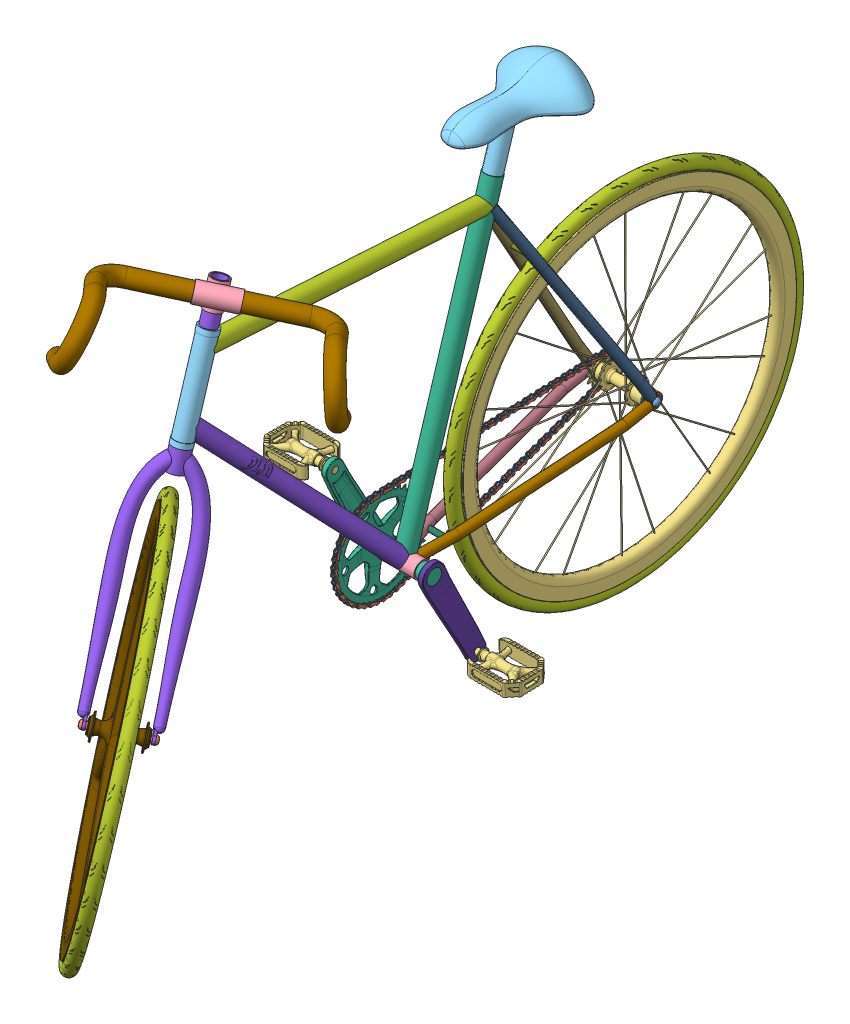
SolidWorks assembly Fixie 2 Virtual, configuration Default. Lengths in mm.
Overall size (654.43 1184.66 1918.44).
126 component instances, 27 part files, 36 mates.
Components (placement in the parent):
- Copy of Axe 2^Fixie 2 Virtual-1: Copy of Axe 2^Fixie 2 Virtual [Default] at (0 85.0139 -432.7378) x (1 0 0) z (0 0.996852 0.079286) size (142 15 15) (virtual)
- Copy of Axe^Fixie 2 Virtual-1: Copy of Axe^Fixie 2 Virtual [Default] at (68.9988 54.6364 630.7845) x (-0.06655 -0.973594 0.21837) z (0.751571 -0.192864 -0.630828) size (15 15 115) (virtual)
- Copy of Back Wheel^Fixie 2 Virtual-1: Copy of Back Wheel^Fixie 2 Virtual [Default] at (0.5 85.0139 -432.7378) x (1 0 0) z (0 0.746338 0.665567) size (100 658.88 658.88) (virtual)
- Copy of cadre^Fixie 2 Virtual-1: Copy of cadre^Fixie 2 Virtual [Défaut] at origin size (140 613.27 908.21) (virtual)
  - tube pedalier^Copy of cadre_Fixie 2 Virtual-1: tube pedalier^Copy of cadre_Fixie 2 Virtual [Défaut] at origin size (73 33 33) (virtual)
  - trou pour fourche^Copy of cadre_Fixie 2 Virtual-2: trou pour fourche^Copy of cadre_Fixie 2 Virtual [Défaut] at (0 502.9172 411.5258) x (0.998411 0.016475 0.053886) z (0 -0.956305 0.292372) size (35 35 185) (virtual)
  - tube de selle^Copy of cadre_Fixie 2 Virtual-1: tube de selle^Copy of cadre_Fixie 2 Virtual [Défaut] at (0 573.7829 -175.423) x (1 0 0) z (0 0.956305 -0.292372) size (32.9 32.9 600.3) (virtual)
  - tube de tete^Copy of cadre_Fixie 2 Virtual-1: tube de tete^Copy of cadre_Fixie 2 Virtual [Défaut] at (0 561.2509 393.6914) x (1 0 0) z (0 0.060491 0.998169) size (32.9 32.9 555.16) (virtual)
  - tube du bas^Copy of cadre_Fixie 2 Virtual-3: tube du bas^Copy of cadre_Fixie 2 Virtual [Défaut] at (0 447.1547 428.5741) x (-1 0 0) z (0 -0.721947 -0.691948) size (32.91 32.9 618.4) (virtual)
  - tube arriere bas^Copy of cadre_Fixie 2 Virtual-2: tube arriere bas^Copy of cadre_Fixie 2 Virtual [Défaut] at origin size (67.83 98.35 411.57) (virtual)
  - tube arriere haut^Copy of cadre_Fixie 2 Virtual-1: tube arriere haut^Copy of cadre_Fixie 2 Virtual [Défaut] at origin size (69.56 441.01 279.99) (virtual)
  - encoche roue^Copy of cadre_Fixie 2 Virtual-7: encoche roue^Copy of cadre_Fixie 2 Virtual [Défaut] at (61 85.0139 -432.7378) x (0 -0.852467 -0.522781) z (-1 0 0) size (54 61.43 6.25) (virtual)
  - Symétrietube arriere haut^Copy of cadre_Fixie 2 Virtual-2: Symétrietube arriere haut^Copy of cadre_Fixie 2 Virtual [Défaut] x (-1 0 0) z (0 0 -1) size (69.56 441.01 279.99) (virtual)
  - Symétrietube arriere bas^Copy of cadre_Fixie 2 Virtual-3: Symétrietube arriere bas^Copy of cadre_Fixie 2 Virtual [Défaut] x (-1 0 0) z (0 0 -1) size (67.83 98.35 411.57) (virtual)
  - Symétrieencoche roue^Copy of cadre_Fixie 2 Virtual-8: Symétrieencoche roue^Copy of cadre_Fixie 2 Virtual [Défaut] at (-61 85.0139 -432.7378) x (0 -0.852467 -0.522781) z (-1 0 0) size (54 61.43 6.25) (virtual)
  - tube consolider 1^Copy of cadre_Fixie 2 Virtual-1: tube consolider 1^Copy of cadre_Fixie 2 Virtual [Défaut] x (0 0 -1) z (1 0 0) size (10 10 30.38) (virtual)
  - tube consolider 2^Copy of cadre_Fixie 2 Virtual-1: tube consolider 2^Copy of cadre_Fixie 2 Virtual [Défaut] x (0 0 -1) z (1 0 0) size (10 10 34.39) (virtual)
- Copy of Crank 2^Fixie 2 Virtual-1: Copy of Crank 2^Fixie 2 Virtual [Default] at (65 -161.4318 -97.9912) x (0 -0.413351 0.910572) z (-1 0 0) size (45 210 26.78) (virtual)
- Copy of Front Wheel^Fixie 2 Virtual-1: Copy of Front Wheel^Fixie 2 Virtual [Default] at (68.9988 54.6364 630.7845) x (-0.751571 0.192864 0.630828) z (0.306423 0.94894 0.074953) size (90 658.88 658.88) (virtual)
- Copy of Inner Chain^Fixie 2 Virtual-1: Copy of Inner Chain^Fixie 2 Virtual [Default] at (-46 13.7146 89.7835) x (1 0 0) z (0 0.988534 -0.151) size (5 8 20.8) (virtual)
- Copy of Outter Chain^Fixie 2 Virtual-1: Copy of Outter Chain^Fixie 2 Virtual [Default] at (-46 26.1669 86.9739) x (1 0 0) z (0 0.957599 -0.288103) size (8.5 8 20.8) (virtual)
- Copy of Pedal 2^Fixie 2 Virtual-1: Copy of Pedal 2^Fixie 2 Virtual [Default] at (-136.5 154.7972 70.2697) x (0 0 1) z (1 0 0) size (80 25 117.5) (virtual)
- Copy of Potence 2^Fixie 2 Virtual-1: Copy of Potence 2^Fixie 2 Virtual [Défaut] at (42.681 674.7582 409.8391) x (-0.659652 -0.219738 -0.718731) z (0.751571 -0.192864 -0.630828) size (98.9 64.61 70) (virtual)
- Copy of selle^Fixie 2 Virtual-1: Copy of selle^Fixie 2 Virtual [Défaut] at (0 662.8695 -204.4368) x (-1 0 0) z (0 0.017452 -0.999848) size (178.5 284.14 238.49) (virtual)
- Copy of Sprocket 2^Fixie 2 Virtual-1: Copy of Sprocket 2^Fixie 2 Virtual [Default] at (-50 0 0) x (-1 0 0) z (0 0.869629 -0.493706) size (135 250.05 212.39) (virtual)
- Copy of Tire^Fixie 2 Virtual-1: Copy of Tire^Fixie 2 Virtual [Default] at (0.5 85.0139 -432.7378) x (1 0 0) z (0 -0.189149 0.981948) size (24.5 700 700) (virtual)
- Copy of Pedal 2^Fixie 2 Virtual-2: Copy of Pedal 2^Fixie 2 Virtual [Default] at (136.5 -154.7972 -70.2697) x (0 0.031063 -0.999517) z (-1 0 0) size (80 25 117.5) (virtual)
- Copy of Tire^Fixie 2 Virtual-2: Copy of Tire^Fixie 2 Virtual [Default] at (68.9988 54.6364 630.7845) x (-0.751571 0.192864 0.630828) z (-0.630828 -0.489733 -0.601845) size (24.5 700 700) (virtual)
- Copy of Inner Chain^Fixie 2 Virtual-50: Copy of Inner Chain^Fixie 2 Virtual [Default] at (-46 38.1023 82.4462) x (1 0 0) z (0 0.907749 -0.419514) size (5 8 20.8) (virtual)
- Copy of Inner Chain^Fixie 2 Virtual-51: Copy of Inner Chain^Fixie 2 Virtual [Default] at (-46 59.4943 68.6265) x (1 0 0) z (0 0.755591 -0.655044) size (5 8 20.8) (virtual)
- Copy of Inner Chain^Fixie 2 Virtual-52: Copy of Inner Chain^Fixie 2 Virtual [Default] at (-46 76.2084 49.4109) x (1 0 0) z (0 0.544024 -0.83907) size (5 8 20.8) (virtual)
- Copy of Inner Chain^Fixie 2 Virtual-53: Copy of Inner Chain^Fixie 2 Virtual [Default] at (-46 86.9306 26.3104) x (1 0 0) z (0 0.289683 -0.957123) size (5 8 20.8) (virtual)
- Copy of Inner Chain^Fixie 2 Virtual-54: Copy of Inner Chain^Fixie 2 Virtual [Default] at (-46 91.0468 1.1482) x (1 0 0) z (0 0.04837 -0.998829) size (5 8 20.8) (virtual)
- Copy of Inner Chain^Fixie 2 Virtual-55: Copy of Inner Chain^Fixie 2 Virtual [Default] at (-46 92.1741 -24.4209) x (1 0 0) z (0 0.042605 -0.999092) size (5 8 20.8) (virtual)
- Copy of Inner Chain^Fixie 2 Virtual-56: Copy of Inner Chain^Fixie 2 Virtual [Default] at (-46 93.2646 -49.9916) x (1 0 0) z (0 0.042605 -0.999092) size (5 8 20.8) (virtual)
- Copy of Inner Chain^Fixie 2 Virtual-57: Copy of Inner Chain^Fixie 2 Virtual [Default] at (-46 94.355 -75.5624) x (1 0 0) z (0 0.042605 -0.999092) size (5 8 20.8) (virtual)
- Copy of Inner Chain^Fixie 2 Virtual-58: Copy of Inner Chain^Fixie 2 Virtual [Default] at (-46 95.4454 -101.1332) x (1 0 0) z (0 0.042605 -0.999092) size (5 8 20.8) (virtual)
- Copy of Inner Chain^Fixie 2 Virtual-59: Copy of Inner Chain^Fixie 2 Virtual [Default] at (-46 96.5358 -126.7039) x (1 0 0) z (0 0.042605 -0.999092) size (5 8 20.8) (virtual)
- Copy of Inner Chain^Fixie 2 Virtual-60: Copy of Inner Chain^Fixie 2 Virtual [Default] at (-46 97.6263 -152.2747) x (1 0 0) z (0 0.042605 -0.999092) size (5 8 20.8) (virtual)
- Copy of Inner Chain^Fixie 2 Virtual-61: Copy of Inner Chain^Fixie 2 Virtual [Default] at (-46 98.7167 -177.8454) x (1 0 0) z (0 0.042605 -0.999092) size (5 8 20.8) (virtual)
- Copy of Inner Chain^Fixie 2 Virtual-62: Copy of Inner Chain^Fixie 2 Virtual [Default] at (-46 99.8071 -203.4162) x (1 0 0) z (0 0.042605 -0.999092) size (5 8 20.8) (virtual)
- Copy of Inner Chain^Fixie 2 Virtual-63: Copy of Inner Chain^Fixie 2 Virtual [Default] at (-46 100.8975 -228.987) x (1 0 0) z (0 0.042605 -0.999092) size (5 8 20.8) (virtual)
- Copy of Inner Chain^Fixie 2 Virtual-64: Copy of Inner Chain^Fixie 2 Virtual [Default] at (-46 101.988 -254.5577) x (1 0 0) z (0 0.042605 -0.999092) size (5 8 20.8) (virtual)
- Copy of Inner Chain^Fixie 2 Virtual-65: Copy of Inner Chain^Fixie 2 Virtual [Default] at (-46 103.0784 -280.1285) x (1 0 0) z (0 0.042605 -0.999092) size (5 8 20.8) (virtual)
- Copy of Inner Chain^Fixie 2 Virtual-66: Copy of Inner Chain^Fixie 2 Virtual [Default] at (-46 104.1688 -305.6992) x (1 0 0) z (0 0.042605 -0.999092) size (5 8 20.8) (virtual)
- Copy of Inner Chain^Fixie 2 Virtual-67: Copy of Inner Chain^Fixie 2 Virtual [Default] at (-46 105.2592 -331.27) x (1 0 0) z (0 0.042605 -0.999092) size (5 8 20.8) (virtual)
- Copy of Inner Chain^Fixie 2 Virtual-68: Copy of Inner Chain^Fixie 2 Virtual [Default] at (-46 106.3497 -356.8408) x (1 0 0) z (0 0.042605 -0.999092) size (5 8 20.8) (virtual)
- Copy of Inner Chain^Fixie 2 Virtual-69: Copy of Inner Chain^Fixie 2 Virtual [Default] at (-46 107.4401 -382.4115) x (1 0 0) z (0 0.042605 -0.999092) size (5 8 20.8) (virtual)
- Copy of Inner Chain^Fixie 2 Virtual-70: Copy of Inner Chain^Fixie 2 Virtual [Default] at (-46 108.5305 -407.9823) x (1 0 0) z (0 0.042605 -0.999092) size (5 8 20.8) (virtual)
- Copy of Inner Chain^Fixie 2 Virtual-71: Copy of Inner Chain^Fixie 2 Virtual [Default] at (-46 108.9178 -433.5444) x (1 0 0) z (0 -0.06729 -0.997733) size (5 8 20.8) (virtual)
- Copy of Inner Chain^Fixie 2 Virtual-72: Copy of Inner Chain^Fixie 2 Virtual [Default] at (-46 96.0116 -453.7333) x (1 0 0) z (0 -0.885831 -0.464009) size (5 8 20.8) (virtual)
- Copy of Inner Chain^Fixie 2 Virtual-73: Copy of Inner Chain^Fixie 2 Virtual [Default] at (-46 72.1801 -452.6641) x (1 0 0) z (0 -0.840718 0.541474) size (5 8 20.8) (virtual)
- Copy of Inner Chain^Fixie 2 Virtual-74: Copy of Inner Chain^Fixie 2 Virtual [Default] at (-46 58.6166 -431.8851) x (1 0 0) z (0 -0.338529 0.940956) size (5 8 20.8) (virtual)
- Copy of Inner Chain^Fixie 2 Virtual-75: Copy of Inner Chain^Fixie 2 Virtual [Default] at (-46 49.9523 -407.8023) x (1 0 0) z (0 -0.338529 0.940956) size (5 8 20.8) (virtual)
- Copy of Inner Chain^Fixie 2 Virtual-76: Copy of Inner Chain^Fixie 2 Virtual [Default] at (-46 41.288 -383.7195) x (1 0 0) z (0 -0.338529 0.940956) size (5 8 20.8) (virtual)
- Copy of Inner Chain^Fixie 2 Virtual-77: Copy of Inner Chain^Fixie 2 Virtual [Default] at (-46 32.6237 -359.6367) x (1 0 0) z (0 -0.338529 0.940956) size (5 8 20.8) (virtual)
- Copy of Inner Chain^Fixie 2 Virtual-78: Copy of Inner Chain^Fixie 2 Virtual [Default] at (-46 23.9594 -335.5538) x (1 0 0) z (0 -0.338529 0.940956) size (5 8 20.8) (virtual)
- Copy of Inner Chain^Fixie 2 Virtual-79: Copy of Inner Chain^Fixie 2 Virtual [Default] at (-46 15.2951 -311.471) x (1 0 0) z (0 -0.338529 0.940956) size (5 8 20.8) (virtual)
- Copy of Inner Chain^Fixie 2 Virtual-80: Copy of Inner Chain^Fixie 2 Virtual [Default] at (-46 6.6307 -287.3882) x (1 0 0) z (0 -0.338529 0.940956) size (5 8 20.8) (virtual)
- Copy of Inner Chain^Fixie 2 Virtual-81: Copy of Inner Chain^Fixie 2 Virtual [Default] at (-46 -2.0336 -263.3053) x (1 0 0) z (0 -0.338529 0.940956) size (5 8 20.8) (virtual)
- Copy of Inner Chain^Fixie 2 Virtual-82: Copy of Inner Chain^Fixie 2 Virtual [Default] at (-46 -10.6979 -239.2225) x (1 0 0) z (0 -0.338529 0.940956) size (5 8 20.8) (virtual)
- Copy of Inner Chain^Fixie 2 Virtual-83: Copy of Inner Chain^Fixie 2 Virtual [Default] at (-46 -19.3622 -215.1397) x (1 0 0) z (0 -0.338529 0.940956) size (5 8 20.8) (virtual)
- Copy of Inner Chain^Fixie 2 Virtual-84: Copy of Inner Chain^Fixie 2 Virtual [Default] at (-46 -28.0265 -191.0569) x (1 0 0) z (0 -0.338529 0.940956) size (5 8 20.8) (virtual)
- Copy of Inner Chain^Fixie 2 Virtual-85: Copy of Inner Chain^Fixie 2 Virtual [Default] at (-46 -36.6908 -166.974) x (1 0 0) z (0 -0.338529 0.940956) size (5 8 20.8) (virtual)
- Copy of Inner Chain^Fixie 2 Virtual-86: Copy of Inner Chain^Fixie 2 Virtual [Default] at (-46 -45.3551 -142.8912) x (1 0 0) z (0 -0.338529 0.940956) size (5 8 20.8) (virtual)
- Copy of Inner Chain^Fixie 2 Virtual-87: Copy of Inner Chain^Fixie 2 Virtual [Default] at (-46 -54.0194 -118.8084) x (1 0 0) z (0 -0.338529 0.940956) size (5 8 20.8) (virtual)
- Copy of Inner Chain^Fixie 2 Virtual-88: Copy of Inner Chain^Fixie 2 Virtual [Default] at (-46 -62.6837 -94.7256) x (1 0 0) z (0 -0.338529 0.940956) size (5 8 20.8) (virtual)
- Copy of Inner Chain^Fixie 2 Virtual-89: Copy of Inner Chain^Fixie 2 Virtual [Default] at (-46 -71.3481 -70.6427) x (1 0 0) z (0 -0.338529 0.940956) size (5 8 20.8) (virtual)
- Copy of Inner Chain^Fixie 2 Virtual-90: Copy of Inner Chain^Fixie 2 Virtual [Default] at (-46 -80.0124 -46.5599) x (1 0 0) z (0 -0.338529 0.940956) size (5 8 20.8) (virtual)
- Copy of Inner Chain^Fixie 2 Virtual-91: Copy of Inner Chain^Fixie 2 Virtual [Default] at (-46 -88.0489 -22.2835) x (1 0 0) z (0 -0.245346 0.969436) size (5 8 20.8) (virtual)
- Copy of Inner Chain^Fixie 2 Virtual-92: Copy of Inner Chain^Fixie 2 Virtual [Default] at (-46 -90.7741 3.0378) x (1 0 0) z (0 0.033447 0.99944) size (5 8 20.8) (virtual)
- Copy of Inner Chain^Fixie 2 Virtual-93: Copy of Inner Chain^Fixie 2 Virtual [Default] at (-46 -86.3621 28.1204) x (1 0 0) z (0 0.309611 0.950863) size (5 8 20.8) (virtual)
- Copy of Inner Chain^Fixie 2 Virtual-94: Copy of Inner Chain^Fixie 2 Virtual [Default] at (-46 -75.1598 50.9919) x (1 0 0) z (0 0.561431 0.827524) size (5 8 20.8) (virtual)
- Copy of Inner Chain^Fixie 2 Virtual-95: Copy of Inner Chain^Fixie 2 Virtual [Default] at (-46 -58.0479 69.8541) x (1 0 0) z (0 0.769108 0.639119) size (5 8 20.8) (virtual)
- Copy of Inner Chain^Fixie 2 Virtual-96: Copy of Inner Chain^Fixie 2 Virtual [Default] at (-46 -36.372 83.224) x (1 0 0) z (0 0.916313 0.400463) size (5 8 20.8) (virtual)
- Copy of Outter Chain^Fixie 2 Virtual-50: Copy of Outter Chain^Fixie 2 Virtual [Default] at (-46 49.2851 76.2898) x (1 0 0) z (0 0.839966 -0.542639) size (8.5 8 20.8) (virtual)
- Copy of Outter Chain^Fixie 2 Virtual-51: Copy of Outter Chain^Fixie 2 Virtual [Default] at (-46 68.5282 59.6075) x (1 0 0) z (0 0.65629 -0.754509) size (8.5 8 20.8) (virtual)
- Copy of Outter Chain^Fixie 2 Virtual-52: Copy of Outter Chain^Fixie 2 Virtual [Default] at (-46 82.3832 38.2384) x (1 0 0) z (0 0.421012 -0.907055) size (8.5 8 20.8) (virtual)
- Copy of Outter Chain^Fixie 2 Virtual-53: Copy of Outter Chain^Fixie 2 Virtual [Default] at (-46 89.7607 13.8627) x (1 0 0) z (0 0.152632 -0.988283) size (8.5 8 20.8) (virtual)
- Copy of Outter Chain^Fixie 2 Virtual-54: Copy of Outter Chain^Fixie 2 Virtual [Default] at (-46 91.6289 -11.6355) x (1 0 0) z (0 0.042605 -0.999092) size (8.5 8 20.8) (virtual)
- Copy of Outter Chain^Fixie 2 Virtual-55: Copy of Outter Chain^Fixie 2 Virtual [Default] at (-46 92.7194 -37.2063) x (1 0 0) z (0 0.042605 -0.999092) size (8.5 8 20.8) (virtual)
- Copy of Outter Chain^Fixie 2 Virtual-56: Copy of Outter Chain^Fixie 2 Virtual [Default] at (-46 93.8098 -62.777) x (1 0 0) z (0 0.042605 -0.999092) size (8.5 8 20.8) (virtual)
- Copy of Outter Chain^Fixie 2 Virtual-57: Copy of Outter Chain^Fixie 2 Virtual [Default] at (-46 94.9002 -88.3478) x (1 0 0) z (0 0.042605 -0.999092) size (8.5 8 20.8) (virtual)
- Copy of Outter Chain^Fixie 2 Virtual-58: Copy of Outter Chain^Fixie 2 Virtual [Default] at (-46 95.9906 -113.9185) x (1 0 0) z (0 0.042605 -0.999092) size (8.5 8 20.8) (virtual)
- Copy of Outter Chain^Fixie 2 Virtual-59: Copy of Outter Chain^Fixie 2 Virtual [Default] at (-46 97.0811 -139.4893) x (1 0 0) z (0 0.042605 -0.999092) size (8.5 8 20.8) (virtual)
- Copy of Outter Chain^Fixie 2 Virtual-60: Copy of Outter Chain^Fixie 2 Virtual [Default] at (-46 98.1715 -165.0601) x (1 0 0) z (0 0.042605 -0.999092) size (8.5 8 20.8) (virtual)
- Copy of Outter Chain^Fixie 2 Virtual-61: Copy of Outter Chain^Fixie 2 Virtual [Default] at (-46 99.2619 -190.6308) x (1 0 0) z (0 0.042605 -0.999092) size (8.5 8 20.8) (virtual)
- Copy of Outter Chain^Fixie 2 Virtual-62: Copy of Outter Chain^Fixie 2 Virtual [Default] at (-46 100.3523 -216.2016) x (1 0 0) z (0 0.042605 -0.999092) size (8.5 8 20.8) (virtual)
- Copy of Outter Chain^Fixie 2 Virtual-63: Copy of Outter Chain^Fixie 2 Virtual [Default] at (-46 101.4428 -241.7723) x (1 0 0) z (0 0.042605 -0.999092) size (8.5 8 20.8) (virtual)
- Copy of Outter Chain^Fixie 2 Virtual-64: Copy of Outter Chain^Fixie 2 Virtual [Default] at (-46 102.5332 -267.3431) x (1 0 0) z (0 0.042605 -0.999092) size (8.5 8 20.8) (virtual)
- Copy of Outter Chain^Fixie 2 Virtual-65: Copy of Outter Chain^Fixie 2 Virtual [Default] at (-46 103.6236 -292.9139) x (1 0 0) z (0 0.042605 -0.999092) size (8.5 8 20.8) (virtual)
- Copy of Outter Chain^Fixie 2 Virtual-66: Copy of Outter Chain^Fixie 2 Virtual [Default] at (-46 104.714 -318.4846) x (1 0 0) z (0 0.042605 -0.999092) size (8.5 8 20.8) (virtual)
- Copy of Outter Chain^Fixie 2 Virtual-67: Copy of Outter Chain^Fixie 2 Virtual [Default] at (-46 105.8045 -344.0554) x (1 0 0) z (0 0.042605 -0.999092) size (8.5 8 20.8) (virtual)
- Copy of Outter Chain^Fixie 2 Virtual-68: Copy of Outter Chain^Fixie 2 Virtual [Default] at (-46 106.8949 -369.6261) x (1 0 0) z (0 0.042605 -0.999092) size (8.5 8 20.8) (virtual)
- Copy of Outter Chain^Fixie 2 Virtual-69: Copy of Outter Chain^Fixie 2 Virtual [Default] at (-46 107.9853 -395.1969) x (1 0 0) z (0 0.042605 -0.999092) size (8.5 8 20.8) (virtual)
- Copy of Outter Chain^Fixie 2 Virtual-70: Copy of Outter Chain^Fixie 2 Virtual [Default] at (-46 109.0757 -420.7677) x (1 0 0) z (0 0.042605 -0.999092) size (8.5 8 20.8) (virtual)
- Copy of Outter Chain^Fixie 2 Virtual-71: Copy of Outter Chain^Fixie 2 Virtual [Default] at (-46 105.0834 -445.3464) x (1 0 0) z (0 -0.531973 -0.846761) size (8.5 8 20.8) (virtual)
- Copy of Outter Chain^Fixie 2 Virtual-72: Copy of Outter Chain^Fixie 2 Virtual [Default] at (-46 83.9515 -456.4155) x (1 0 0) z (0 -0.998995 0.044822) size (8.5 8 20.8) (virtual)
- Copy of Outter Chain^Fixie 2 Virtual-73: Copy of Outter Chain^Fixie 2 Virtual [Default] at (-46 63.7917 -443.5526) x (1 0 0) z (0 -0.470274 0.882521) size (8.5 8 20.8) (virtual)
- Copy of Outter Chain^Fixie 2 Virtual-74: Copy of Outter Chain^Fixie 2 Virtual [Default] at (-46 54.2845 -419.8437) x (1 0 0) z (0 -0.338529 0.940956) size (8.5 8 20.8) (virtual)
- Copy of Outter Chain^Fixie 2 Virtual-75: Copy of Outter Chain^Fixie 2 Virtual [Default] at (-46 45.6202 -395.7609) x (1 0 0) z (0 -0.338529 0.940956) size (8.5 8 20.8) (virtual)
- Copy of Outter Chain^Fixie 2 Virtual-76: Copy of Outter Chain^Fixie 2 Virtual [Default] at (-46 36.9558 -371.6781) x (1 0 0) z (0 -0.338529 0.940956) size (8.5 8 20.8) (virtual)
- Copy of Outter Chain^Fixie 2 Virtual-77: Copy of Outter Chain^Fixie 2 Virtual [Default] at (-46 28.2915 -347.5952) x (1 0 0) z (0 -0.338529 0.940956) size (8.5 8 20.8) (virtual)
- Copy of Outter Chain^Fixie 2 Virtual-78: Copy of Outter Chain^Fixie 2 Virtual [Default] at (-46 19.6272 -323.5124) x (1 0 0) z (0 -0.338529 0.940956) size (8.5 8 20.8) (virtual)
- Copy of Outter Chain^Fixie 2 Virtual-79: Copy of Outter Chain^Fixie 2 Virtual [Default] at (-46 10.9629 -299.4296) x (1 0 0) z (0 -0.338529 0.940956) size (8.5 8 20.8) (virtual)
- Copy of Outter Chain^Fixie 2 Virtual-80: Copy of Outter Chain^Fixie 2 Virtual [Default] at (-46 2.2986 -275.3468) x (1 0 0) z (0 -0.338529 0.940956) size (8.5 8 20.8) (virtual)
- Copy of Outter Chain^Fixie 2 Virtual-81: Copy of Outter Chain^Fixie 2 Virtual [Default] at (-46 -6.3657 -251.2639) x (1 0 0) z (0 -0.338529 0.940956) size (8.5 8 20.8) (virtual)
- Copy of Outter Chain^Fixie 2 Virtual-82: Copy of Outter Chain^Fixie 2 Virtual [Default] at (-46 -15.03 -227.1811) x (1 0 0) z (0 -0.338529 0.940956) size (8.5 8 20.8) (virtual)
- Copy of Outter Chain^Fixie 2 Virtual-83: Copy of Outter Chain^Fixie 2 Virtual [Default] at (-46 -23.6943 -203.0983) x (1 0 0) z (0 -0.338529 0.940956) size (8.5 8 20.8) (virtual)
- Copy of Outter Chain^Fixie 2 Virtual-84: Copy of Outter Chain^Fixie 2 Virtual [Default] at (-46 -32.3587 -179.0155) x (1 0 0) z (0 -0.338529 0.940956) size (8.5 8 20.8) (virtual)
- Copy of Outter Chain^Fixie 2 Virtual-85: Copy of Outter Chain^Fixie 2 Virtual [Default] at (-46 -41.023 -154.9326) x (1 0 0) z (0 -0.338529 0.940956) size (8.5 8 20.8) (virtual)
- Copy of Outter Chain^Fixie 2 Virtual-86: Copy of Outter Chain^Fixie 2 Virtual [Default] at (-46 -49.6873 -130.8498) x (1 0 0) z (0 -0.338529 0.940956) size (8.5 8 20.8) (virtual)
- Copy of Outter Chain^Fixie 2 Virtual-87: Copy of Outter Chain^Fixie 2 Virtual [Default] at (-46 -58.3516 -106.767) x (1 0 0) z (0 -0.338529 0.940956) size (8.5 8 20.8) (virtual)
- Copy of Outter Chain^Fixie 2 Virtual-88: Copy of Outter Chain^Fixie 2 Virtual [Default] at (-46 -67.0159 -82.6841) x (1 0 0) z (0 -0.338529 0.940956) size (8.5 8 20.8) (virtual)
- Copy of Outter Chain^Fixie 2 Virtual-89: Copy of Outter Chain^Fixie 2 Virtual [Default] at (-46 -75.6802 -58.6013) x (1 0 0) z (0 -0.338529 0.940956) size (8.5 8 20.8) (virtual)
- Copy of Outter Chain^Fixie 2 Virtual-90: Copy of Outter Chain^Fixie 2 Virtual [Default] at (-46 -84.3287 -34.5128) x (1 0 0) z (0 -0.336062 0.94184) size (8.5 8 20.8) (virtual)
- Copy of Outter Chain^Fixie 2 Virtual-91: Copy of Outter Chain^Fixie 2 Virtual [Default] at (-46 -90.3034 -9.7188) x (1 0 0) z (0 -0.107006 0.994258) size (8.5 8 20.8) (virtual)
- Copy of Outter Chain^Fixie 2 Virtual-92: Copy of Outter Chain^Fixie 2 Virtual [Default] at (-46 -89.4516 15.7345) x (1 0 0) z (0 0.17324 0.98488) size (8.5 8 20.8) (virtual)
- Copy of Outter Chain^Fixie 2 Virtual-93: Copy of Outter Chain^Fixie 2 Virtual [Default] at (-46 -81.5665 39.9507) x (1 0 0) z (0 0.439865 0.898064) size (8.5 8 20.8) (virtual)
- Copy of Outter Chain^Fixie 2 Virtual-94: Copy of Outter Chain^Fixie 2 Virtual [Default] at (-46 -67.2683 61.0258) x (1 0 0) z (0 0.671906 0.740637) size (8.5 8 20.8) (virtual)
- Copy of Outter Chain^Fixie 2 Virtual-95: Copy of Outter Chain^Fixie 2 Virtual [Default] at (-46 -47.6809 77.3026) x (1 0 0) z (0 0.851117 0.524976) size (8.5 8 20.8) (virtual)
- Copy of Outter Chain^Fixie 2 Virtual-96: Copy of Outter Chain^Fixie 2 Virtual [Default] at (-46 -24.3446 87.5014) x (1 0 0) z (0 0.963408 0.268039) size (8.5 8 20.8) (virtual)
- Copy of Inner Chain^Fixie 2 Virtual-97: Copy of Inner Chain^Fixie 2 Virtual [Default] at (-46 -11.8363 90.0503) x (1 0 0) z (0 0.991472 0.13032) size (5 8 20.8) (virtual)
- Copy of Outter Chain^Fixie 2 Virtual-97: Copy of Outter Chain^Fixie 2 Virtual [Default] at (-46 0.9058 90.8204) x (1 0 0) z (0 0.99995 -0.009973) size (8.5 8 20.8) (virtual)
- Copy of fourche^Fixie 2 Virtual-2: Copy of fourche^Fixie 2 Virtual [Défaut<Brut d'usinage>] at (0 376.3038 450.2354) x (0.751571 -0.192864 -0.630828) z (0.659652 0.219738 0.718731) size (141.09 668.83 129.54) (virtual)
- Copy of Guidon 3^Fixie 2 Virtual-1: Copy of Guidon 3^Fixie 2 Virtual [Défaut] at (42.681 674.7582 409.8391) x (-0.751571 0.192864 0.630828) z (0 -0.956305 0.292372) size (435.54 175.85 149.6) (virtual)
Mates (geometry in assembly coordinates):
- Concentric2: concentric anti-aligned: cylinder of Copy of Pedal 2^Fixie 2 Virtual-1 through (-65 154.7972 70.2697) axis (1 0 0) radius 6.25; cylinder of Copy of Sprocket 2^Fixie 2 Virtual-1 through (127.2601 154.7972 70.2697) axis (-1 0 0) radius 6.25
- Coincident1: coincident aligned: plane of Copy of Pedal 2^Fixie 2 Virtual-1 through (-65 154.7972 64.0197) normal (1 0 0); plane of Copy of Sprocket 2^Fixie 2 Virtual-1 through (-65 145.842 41.4948) normal (1 0 0)
- Concentric4: concentric aligned: cylinder of cadre-1/tube de selle^cadre-1 through (0 -15.78 4.8244) axis (0 0.956305 -0.292372) radius 15.55; cylinder of selle-1 through (0 438.8555 -134.1716) axis (0 0.956305 -0.292372) radius 15.55
- Coincident3: coincident aligned: plane of Copy of Crank 2^Fixie 2 Virtual-1 through (60 -23.0031 14.2676) normal (1 0 0); plane of Copy of Sprocket 2^Fixie 2 Virtual-1 through (60 0 0) normal (1 0 0)
- Parallel1: parallel anti-aligned: plane of Copy of Crank 2^Fixie 2 Virtual-1 through (73.3784 -131.2298 -34.8616) normal (0.992278 0.112943 0.05127); plane of Copy of Sprocket 2^Fixie 2 Virtual-1 through (-61.4672 35.3565 -8.6598) normal (-0.992278 -0.112943 -0.05127)
- Concentric14: concentric aligned: cylinder of Copy of Crank 2^Fixie 2 Virtual-1 through (300.6103 -154.7972 -70.2697) axis (-1 0 0) radius 6.25; cylinder of Copy of Pedal 2^Fixie 2 Virtual-2 through (65 -154.7972 -70.2697) axis (-1 0 0) radius 6.25
- Coincident6: coincident aligned: plane of Copy of Crank 2^Fixie 2 Virtual-1 through (65 -180.0326 -57.0155) normal (-1 0 0); plane of Copy of Pedal 2^Fixie 2 Virtual-2 through (65 -154.9913 -64.0227) normal (-1 0 0)
- Concentric15: concentric aligned: cylinder of cadre-1/tube de selle^cadre-1 through (0 -15.78 4.8244) axis (0 0.956305 -0.292372) radius 16.45
- Concentric16: concentric anti-aligned: cylinder of cadre-1/tube pedalier^cadre-1 through (36.5 0 0) axis (-1 0 0) radius 16.5
- Concentric18: concentric anti-aligned: circle of Back Wheel-1; circle of Tire-1
- Coincident14: coincident anti-aligned: plane of Copy of Back Wheel^Fixie 2 Virtual-1 through (9.5 85.0139 -432.7378) normal (-1 0 0); plane of Copy of Tire^Fixie 2 Virtual-1 through (9.5 406.5431 -370.8029) normal (1 0 0)
- Concentric19: concentric anti-aligned: cylinder of Axe 2-1 through (-71 85.0139 -432.7378) axis (-1 0 0) radius 6; cylinder of cadre-1/encoche roue^cadre-7 through (58.5 85.0139 -432.7378) axis (1 0 0) radius 6
- Concentric20: concentric aligned: cylinder of Axe 2-1 through (-71 85.0139 -432.7378) axis (-1 0 0) radius 6; cylinder of Copy of Back Wheel^Fixie 2 Virtual-1 through (-87.3208 85.0139 -432.7378) axis (-1 0 0) radius 9.5
- Coincident16: coincident anti-aligned: plane of Axe 2-1 through (-64.75 77.5375 -433.3324) normal (1 0 0); plane of cadre-1/Symétrieencoche roue^cadre-8 through (-64.75 85.0139 -432.7378) normal (-1 0 0)
- Width2: width aligned: plane of cadre-1/Symétrieencoche roue^cadre-8 through (-58.5 85.0139 -432.7378) normal (1 0 0); plane of cadre-1/encoche roue^cadre-7 through (58.5 85.0139 -432.7378) normal (-1 0 0); plane of Copy of Back Wheel^Fixie 2 Virtual-1 through (50 94.3318 -443.1865) normal (1 0 0); plane of Copy of Back Wheel^Fixie 2 Virtual-1 through (-50 94.3318 -443.1865) normal (-1 0 0)
- Concentric21: concentric aligned: circle of Front Wheel-1; circle of Tire-2
- Coincident18: coincident anti-aligned: plane of Copy of Front Wheel^Fixie 2 Virtual-1 through (62.2347 56.3721 636.4619) normal (0.751571 -0.192864 -0.630828); plane of Copy of Tire^Fixie 2 Virtual-2 through (-0.9166 334.7857 476.1037) normal (-0.751571 0.192864 0.630828)
- Concentric23: concentric aligned: cylinder of cadre-1/tube pedalier^cadre-1 through (36.5 0 0) axis (-1 0 0) radius 14.3; cylinder of Copy of Sprocket 2^Fixie 2 Virtual-1 through (60 0 0) axis (-1 0 0) radius 14.3
- Concentric24: concentric aligned: cylinder of Copy of Crank 2^Fixie 2 Virtual-1 through (300.6103 0 0) axis (-1 0 0) radius 14.3; cylinder of Copy of Sprocket 2^Fixie 2 Virtual-1 through (60 0 0) axis (-1 0 0) radius 14.3
- Width4: width aligned: plane of cadre-1/tube pedalier^cadre-1 through (36.5 0 0) normal (1 0 0); plane of cadre-1/tube pedalier^cadre-1 through (-36.5 0 0) normal (-1 0 0); plane of Copy of Crank 2^Fixie 2 Virtual-1 through (50 -23.0031 14.2676) normal (-1 0 0); plane of Copy of Sprocket 2^Fixie 2 Virtual-1 through (-50 0 0) normal (1 0 0)
- LimitDistance1: limit distance = 98.9076 mm anti-aligned: plane of selle-1 through (0 668.3687 -204.3408) normal (0 -0.956305 0.292372); plane of cadre-1/tube de selle^cadre-1 through (0 573.7829 -175.423) normal (0 0.956305 -0.292372)
- Parallel5: parallel anti-aligned: plane of selle-1 through (0 662.8695 -204.4368) normal (-1 0 0)
- GearMate1: gear = 12 : 45 mm: circle of Sprocket 2-1; circle of Back Wheel-1
- GearMate4: gear = 179.0424 : 20.2 mm: circle of Outter Chain-1; circle of Sprocket 2-1
- Concentric26: concentric anti-aligned: cylinder of Copy of Potence 2^Fixie 2 Virtual-1 through (16.376 681.5085 431.9181) axis (0.751571 -0.192864 -0.630828) radius 15.9; cylinder of Copy of Guidon 3^Fixie 2 Virtual-1 through (42.681 674.7582 409.8391) axis (-0.751571 0.192864 0.630828) radius 15.9
- Concentric27: concentric anti-aligned: cylinder of cadre-1/trou pour fourche^cadre-2 through (0 414.459 438.5702) axis (0 0.956305 -0.292372) radius 14.3; cylinder of Copy of fourche^Fixie 2 Virtual-2 through (0 663.6836 362.3746) axis (0 -0.956305 0.292372) radius 14.3
- Coincident20: coincident anti-aligned: plane of cadre-1/trou pour fourche^cadre-2 through (0 414.459 438.5702) normal (0 -0.956305 0.292372); plane of Copy of fourche^Fixie 2 Virtual-2 through (30.3894 424.5813 471.6788) normal (0 0.956305 -0.292372)
- Concentric28: concentric anti-aligned: cylinder of Copy of Potence 2^Fixie 2 Virtual-1 through (0 615.8684 376.9932) axis (0 0.956305 -0.292372) radius 14.3; cylinder of Copy of fourche^Fixie 2 Virtual-2 through (0 663.6836 362.3746) axis (0 -0.956305 0.292372) radius 12.084
- Coincident22: coincident aligned: plane of Copy of Potence 2^Fixie 2 Virtual-1 through (0 663.6836 362.3746) normal (0 0.956305 -0.292372); plane of Copy of fourche^Fixie 2 Virtual-2 through (0 663.6836 362.3746) normal (0 0.956305 -0.292372)
- Concentric29: concentric aligned: cylinder of Copy of Axe^Fixie 2 Virtual-1 through (112.2142 43.5467 594.5118) axis (0.751571 -0.192864 -0.630828) radius 6; cylinder of Copy of fourche^Fixie 2 Virtual-2 through (15.9808 68.2415 675.285) axis (0.751571 -0.192864 -0.630828) radius 6
- Coincident23: coincident anti-aligned: plane of Copy of Axe^Fixie 2 Virtual-1 through (24.6192 63.8457 658.3187) normal (0.751571 -0.192864 -0.630828); plane of Copy of fourche^Fixie 2 Virtual-2 through (-39.4575 386.4291 483.3539) normal (-0.751571 0.192864 0.630828)
- Concentric30: concentric aligned: cylinder of Copy of Axe^Fixie 2 Virtual-1 through (112.2142 43.5467 594.5118) axis (0.751571 -0.192864 -0.630828) radius 6; cylinder of Copy of Front Wheel^Fixie 2 Virtual-1 through (101.3164 46.3432 603.6588) axis (0.751571 -0.192864 -0.630828) radius 8.5
- Width5: width aligned: plane of Copy of fourche^Fixie 2 Virtual-2 through (-35.6996 385.4648 480.1998) normal (0.751571 -0.192864 -0.630828); plane of Copy of fourche^Fixie 2 Virtual-2 through (35.6996 367.1428 420.2711) normal (-0.751571 0.192864 0.630828); plane of Copy of Front Wheel^Fixie 2 Virtual-1 through (98.3101 47.1147 606.1821) normal (0.751571 -0.192864 -0.630828); plane of Copy of Front Wheel^Fixie 2 Virtual-1 through (39.6875 62.1581 655.3868) normal (-0.751571 0.192864 0.630828)
- ProfileCenter1: profile center = 97 mm anti-aligned: plane of Copy of Potence 2^Fixie 2 Virtual-1 through (68.986 668.008 387.7601) normal (0.751571 -0.192864 -0.630828); circle of Guidon 3-1
- Parallel6: parallel anti-aligned: plane of Copy of fourche^Fixie 2 Virtual-2 through (0 376.3038 450.2354) normal (0 0.956305 -0.292372); plane of Copy of Guidon 3^Fixie 2 Virtual-1 through (42.681 674.7582 409.8391) normal (0 -0.956305 0.292372)
- Parallel7: parallel anti-aligned: cylinder of Copy of fourche^Fixie 2 Virtual-2 through (104.5969 45.5165 600.6865) axis (0.751571 -0.192864 -0.630828) radius 8; cylinder of Copy of Guidon 3^Fixie 2 Virtual-1 through (42.681 674.7582 409.8391) axis (-0.751571 0.192864 0.630828) radius 15.9
